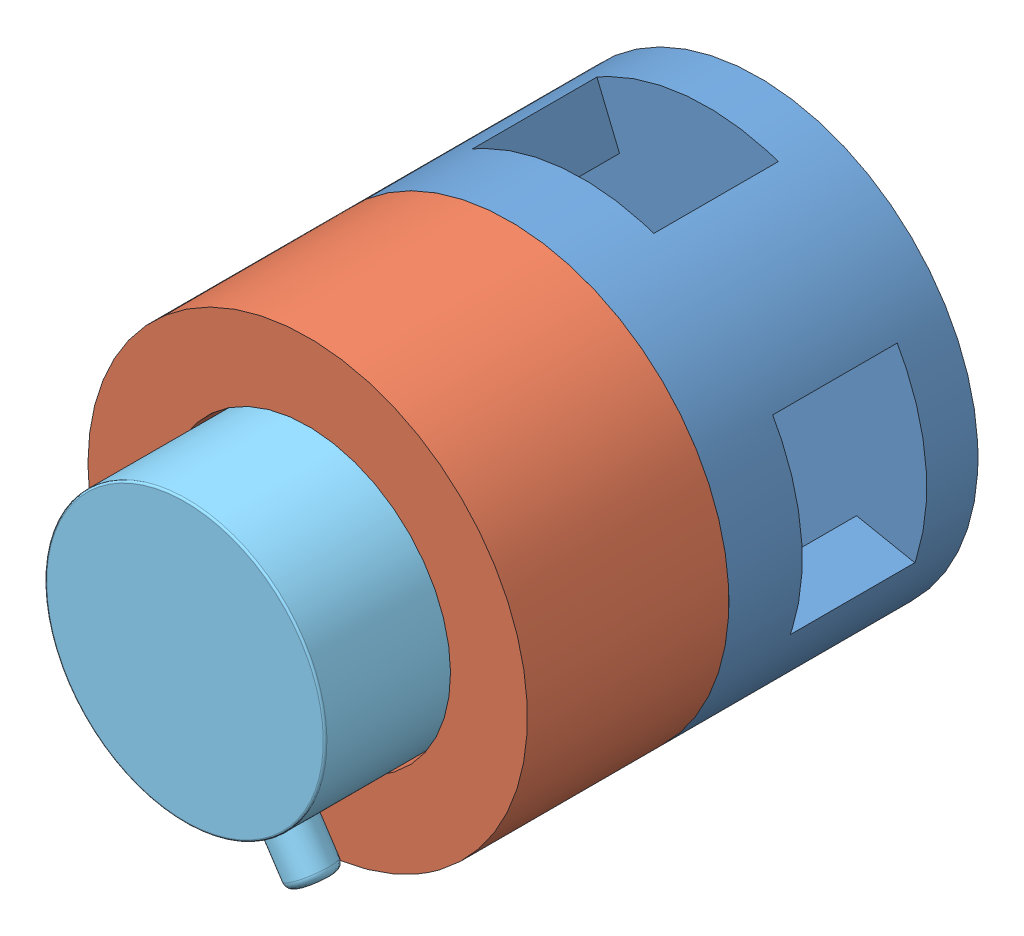
SolidWorks assembly drive_encoder, configuration Default. Lengths in mm.
Overall size (83.12 83.12 78.25).
7 component instances, 6 part files, 5 mates.
Components (placement in the parent):
- drive_encoder_hub-1: drive_encoder_hub [Default] at (55.8382 53.0081 13.6678) size (60 60 35.01)
- drive_encoder_mount-1: drive_encoder_mount [Default] at (55.8382 53.0081 47.6678) x (0.55035 -0.834934 0) z (0 0 1) size (60 60 38.48)
- ROTARY ENCODER orange.step-1: ROTARY ENCODER orange.step [Default] at (55.8382 53.0081 93.9178) x (-0.834934 -0.55035 0) z (0 0 -1) size (38.25 44.12 52.95)
  - Component1.step-1: Component1.step [Default] at origin size (38.25 38.25 7)
  - 4668K121_Permanently Lubricated Stainless Steel Ball Bearing.step-1: 4668K121_Permanently Lubricated Stainless Steel Ball Bearing.step [Default] at (0 0 38.75) size (15 15 5)
  - ROTARY ENCODER rohit.step-1: ROTARY ENCODER rohit.step [Default] at origin size (38.25 44.12 32.25)
  - ROTARY ENCODER rohit-0.step-1: ROTARY ENCODER rohit-0.step [Default] at origin size (5.49 6 20)
Mates (geometry in assembly coordinates):
- Coincident1: coincident anti-aligned: plane of drive_encoder_hub-1 through (55.8382 53.0081 47.6678) normal (0 0 1); plane of drive_encoder_mount-1 through (55.8382 53.0081 47.6678) normal (0 0 -1)
- Concentric1: concentric aligned: cylinder of drive_encoder_hub-1 through (55.8382 53.0081 20.6678) axis (0 0 -1) radius 4; cylinder of drive_encoder_mount-1 through (55.8382 53.0081 75.1678) axis (0 0 -1) radius 19.5
- Concentric2: concentric aligned: cylinder of drive_encoder_mount-1 through (42.4269 59.7266 75.1678) axis (0 0 1) radius 1.5; cylinder of ROTARY ENCODER orange.step-1/ROTARY ENCODER rohit.step-1 through (42.4269 59.7266 57.6678) axis (0 0 1) radius 1.2645
- Concentric3: concentric aligned: cylinder of drive_encoder_mount-1 through (55.8382 53.0081 75.1678) axis (0 0 -1) radius 19.5; cylinder of ROTARY ENCODER orange.step-1/ROTARY ENCODER rohit.step-1 through (55.8382 53.0081 93.9178) axis (0 0 -1) radius 19.125
- Coincident2: coincident anti-aligned: plane of drive_encoder_mount-1 through (55.8382 53.0081 57.6678) normal (0 0 1); plane of ROTARY ENCODER orange.step-1/Component1.step-1 through (55.8382 53.0081 57.6678) normal (0 0 -1)
